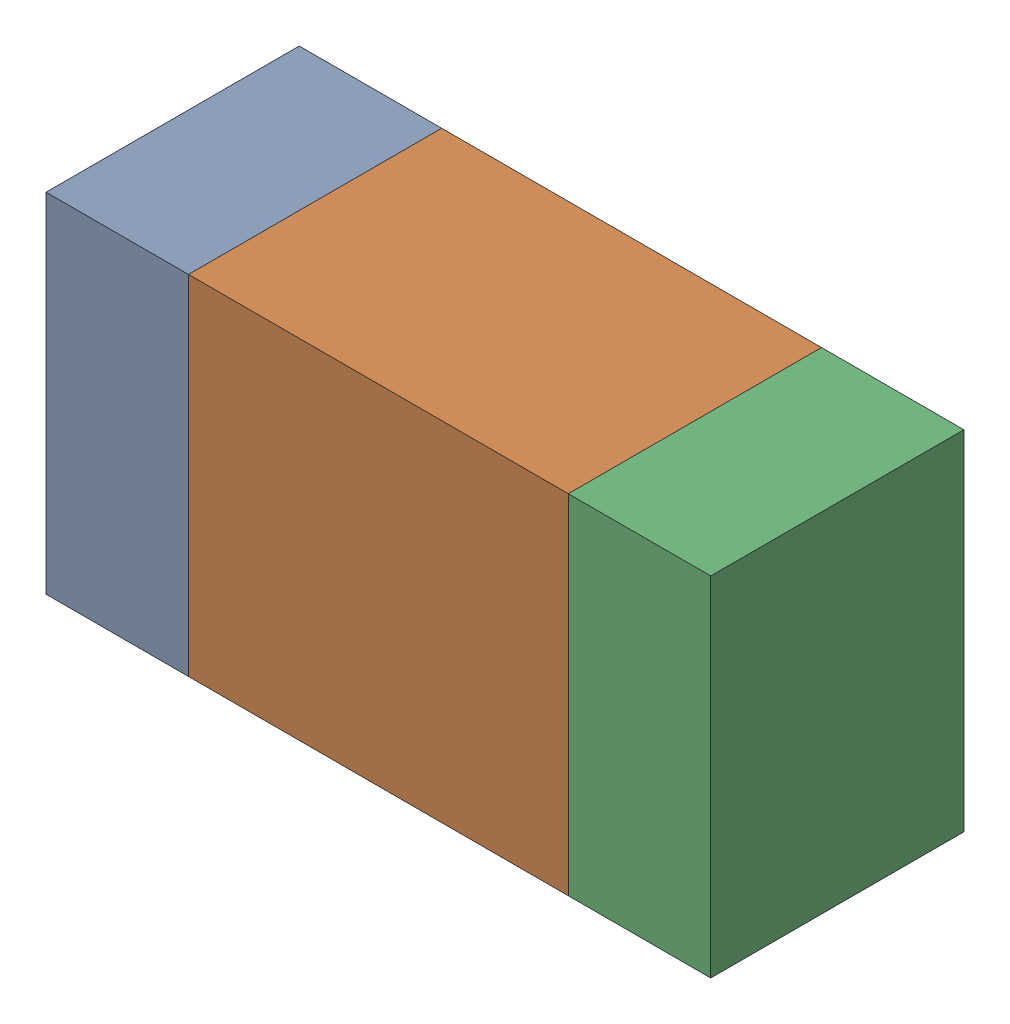
SolidWorks assembly R321_1PCB, configuration Default. Lengths in mm.
Overall size (1.05 0.55 0.4).
6 component instances, 2 part files, 0 mates.
Components (placement in the parent):
- 854785432-1: 854785432 [Default] at (137.0876 116.7001 -2.0638) size (0.22 0.55 0.4)
  - Extruded-1: Extruded [Default] at origin size (0.22 0.55 0.4)
- 854785568-1: 854785568 [Default] at (137.5001 116.7001 -2.0638) size (0.6 0.55 0.4)
  - Extruded_2-1: Extruded_2 [Default] at origin size (0.6 0.55 0.4)
- 854785432-2: 854785432 [Default] at (137.9126 116.7001 -2.0638) size (0.22 0.55 0.4)
  - Extruded-1: Extruded [Default] at origin size (0.22 0.55 0.4)
